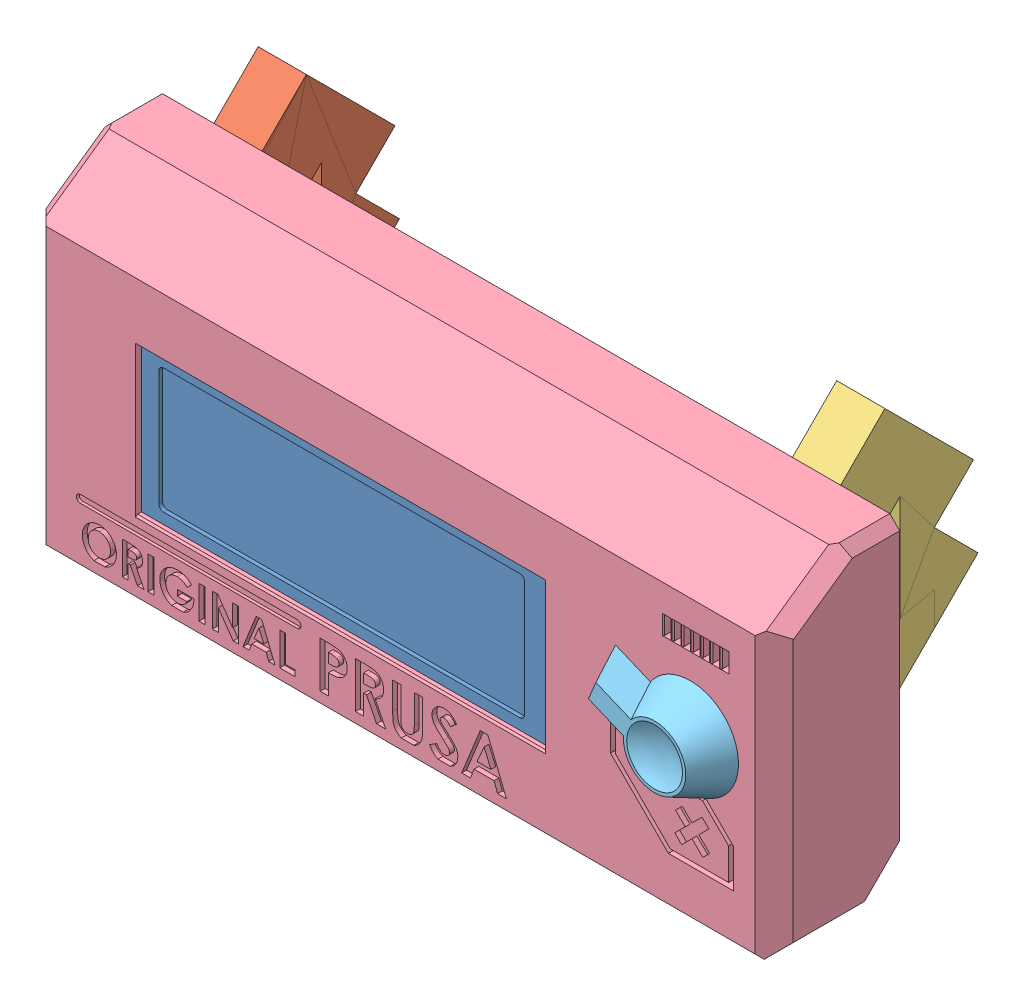
SolidWorks assembly LCD Assembly, configuration Default. Lengths in mm.
Overall size (155 84.79 80.03).
5 component instances, 5 part files, 13 mates.
Components (placement in the parent):
- LCD Board-1: LCD Board [Default] at (45.5138 89.6171 111.3378) size (150 63 29.71)
- lcd-supports1-1: lcd-supports1 [Default] at (-9.0362 59.8671 105.6378) x (0 -0.707107 0.707107) z (-1 0 0) size (65.69 47.48 20)
- lcd-supports2-1: lcd-supports2 [Default] at (110.9738 59.8671 105.6378) x (0 -0.707107 0.707107) z (-1 0 0) size (65.69 47.48 10)
- LCD-cover-ORIGINAL-MK3-1: LCD-cover-ORIGINAL-MK3 [Default] at (45.7638 107.5671 124.7378) x (1 0 0) z (0 0 -1) size (155 70 26.06)
- LCD-KNOB-1: LCD-KNOB [Default] at (104.2929 89.8433 126.2378) x (-0.386654 -0.922225 0) z (0 0 1) size (20 27.64 8.79)
Mates (geometry in assembly coordinates):
- Coincident1: coincident anti-aligned: plane of LCD Board-1 through (45.5138 89.6171 109.6378) normal (0 0 -1); plane of lcd-supports1-1 through (-4.0362 116.3671 109.6378) normal (0 0 1)
- Coincident5: coincident anti-aligned: plane of LCD Board-1 through (45.5138 89.6171 109.6378) normal (0 0 -1); plane of lcd-supports2-1 through (111.9738 61.3671 109.6378) normal (0 0 1)
- Parallel1: parallel anti-aligned: plane of LCD Board-1 through (-29.4862 62.1171 109.6378) normal (0 -1 0); plane of lcd-supports2-1 through (111.9738 61.3671 109.6378) normal (0 1 0)
- Parallel2: parallel anti-aligned: plane of LCD Board-1 through (-29.4862 62.1171 109.6378) normal (0 -1 0); plane of lcd-supports1-1 through (-8.0362 61.3671 109.6378) normal (0 1 0)
- Parallel3: parallel anti-aligned: plane of LCD Board-1 through (-29.4862 62.1171 109.6378) normal (0 -1 0); plane of LCD-cover-ORIGINAL-MK3-1 through (-29.7362 60.7671 110.2378) normal (0 1 0)
- Concentric3: concentric aligned: cylinder of LCD Board-1 through (-26.7362 64.8671 111.3378) axis (0 0 -1) radius 1.5; cylinder of LCD-cover-ORIGINAL-MK3-1 through (-26.7362 64.8671 121.7378) axis (0 0 -1) radius 1.4
- Coincident7: coincident anti-aligned: plane of LCD Board-1 through (45.5138 89.6171 111.3378) normal (0 1 0); plane of lcd-supports1-1 through (-9.0362 89.6171 105.6378) normal (0 -1 0)
- Coincident8: coincident anti-aligned: plane of LCD Board-1 through (45.5138 89.6171 111.3378) normal (0 1 0); plane of lcd-supports2-1 through (110.9738 89.6171 105.6378) normal (0 -1 0)
- Coincident9: coincident: plane of LCD Board-1 through (45.5138 89.6171 123.5378) normal (0 0 1); line of LCD-cover-ORIGINAL-MK3-1 through (-8.7362 69.0671 123.5378) axis (1 0 0)
- Distance1: distance = 120.01 mm anti-aligned: plane of lcd-supports2-1 through (105.9738 59.8671 105.6378) normal (-1 0 0); plane of lcd-supports1-1 through (-14.0362 59.8671 105.6378) normal (1 0 0)
- Distance2: distance = 0.7 mm anti-aligned: plane of LCD-cover-ORIGINAL-MK3-1 through (-29.7362 122.2671 124.7378) normal (1 0 0); plane of lcd-supports1-1 through (-29.0362 62.8671 102.6378) normal (-1 0 0)
- Concentric4: concentric anti-aligned: cylinder of LCD Board-1 through (107.8138 88.3671 122.5378) axis (0 0 -1) radius 3; circle of LCD-KNOB-1
- Coincident10: coincident anti-aligned: plane of LCD Board-1 through (45.5138 89.6171 130.5378) normal (0 0 1); plane of LCD-KNOB-1 through (107.8138 88.3671 130.5378) normal (0 0 -1)
